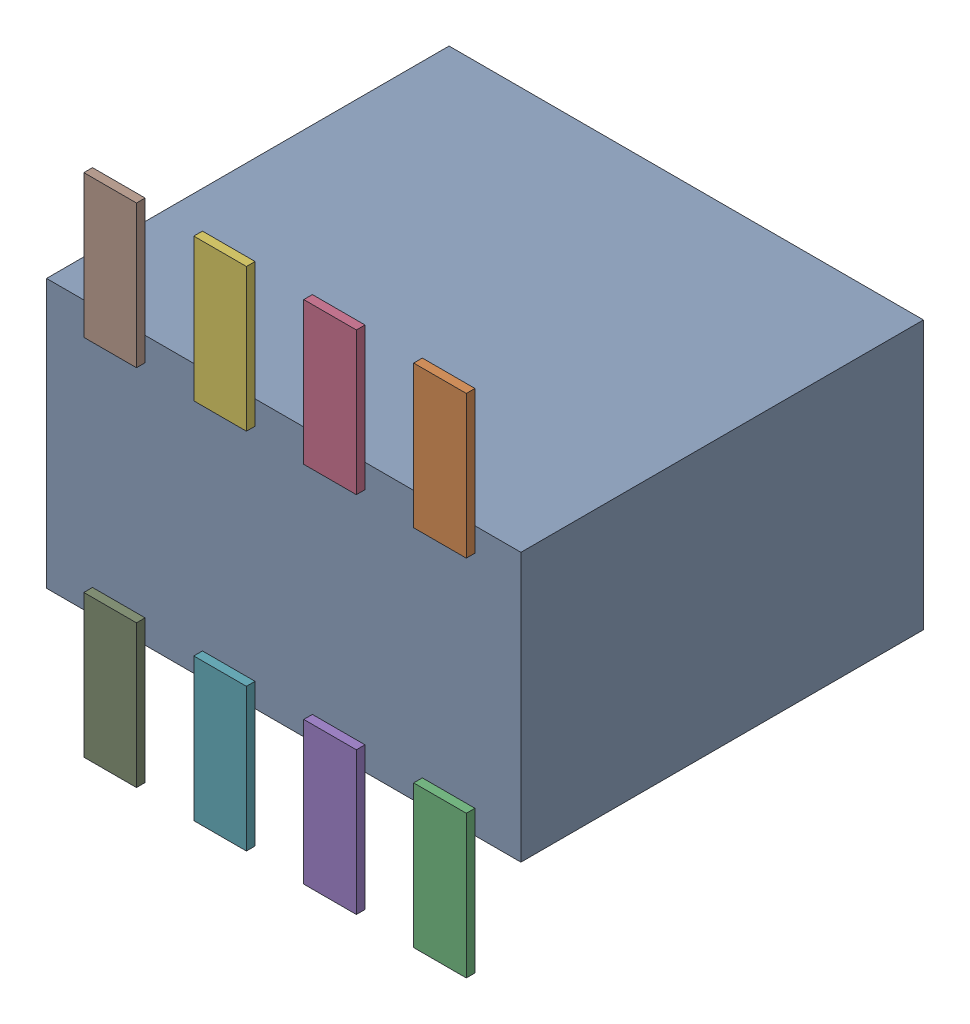
SolidWorks assembly J1, configuration Default. Lengths in mm.
Overall size (5.48 5.85 4.75).
3 component instances, 2 part files, 0 mates.
Components (placement in the parent):
- 9452610336-1: 9452610336 [Default] at (39.751 98.484 -1.0914) x (-1 0 0) z (0 0 -1) size (5.48 5.85 4.75)
  - Body-0-1: Body-0 [Default] at (0 0 0.1) size (5.48 3.1 4.65)
  - Pins-1-1: Pins-1 [Default] at origin size (4.42 5.85 0.1)
